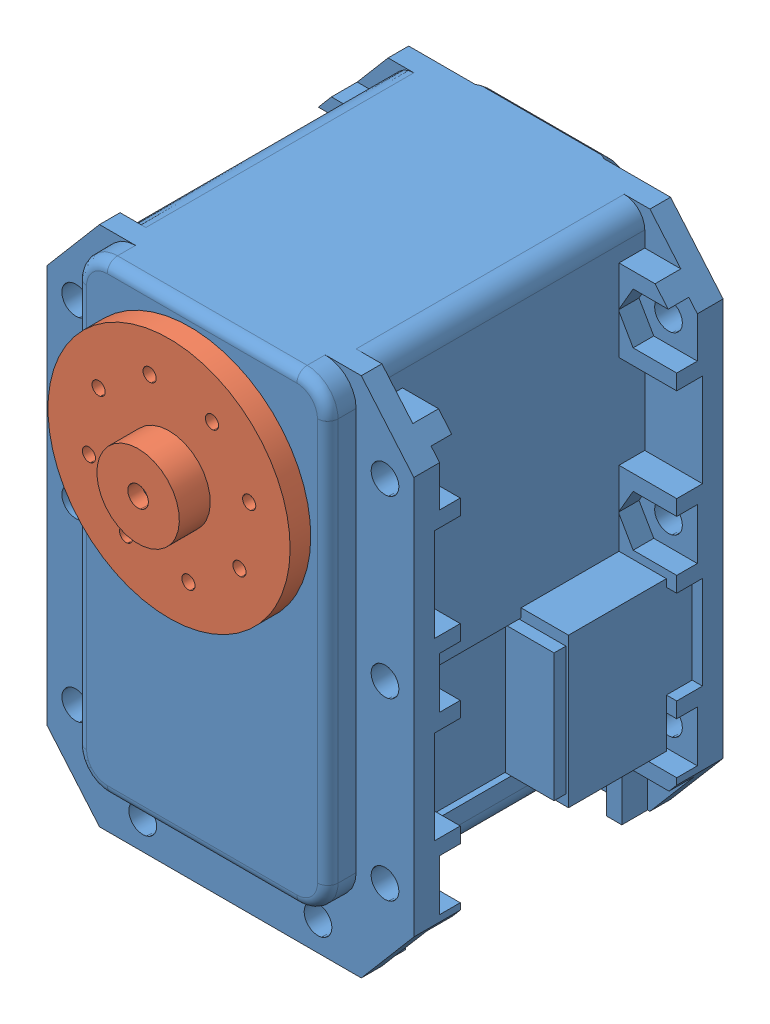
SolidWorks assembly MX-28, configuration Default. Lengths in mm.
Overall size (35.6 54.75 43.2).
2 component instances, 2 part files, 2 mates.
Components (placement in the parent):
- MX-28 SERVO-1: MX-28 SERVO [Default] at (16.2555 37.787 39.9618) size (35.6 50.71 41.85)
- Dynamixel_28T_servohorn-1: Dynamixel_28T_servohorn [Default] at (16.2555 37.787 58.9118) x (0.853673 -0.52081 0) z (0 0 1) size (23.49 23.49 6)
Mates (geometry in assembly coordinates):
- Distance1: distance = 0.2 mm anti-aligned: plane of MX-28 SERVO-1 through (4.6075 4.927 57.7118) normal (0 0 1); plane of Dynamixel_28T_servohorn-1 through (16.2555 37.787 57.9118) normal (0 0 -1)
- Concentric1: concentric anti-aligned: circle of MX-28 SERVO-1; cylinder of Dynamixel_28T_servohorn-1 through (16.2555 37.787 63.9118) axis (0 0 -1) radius 4
